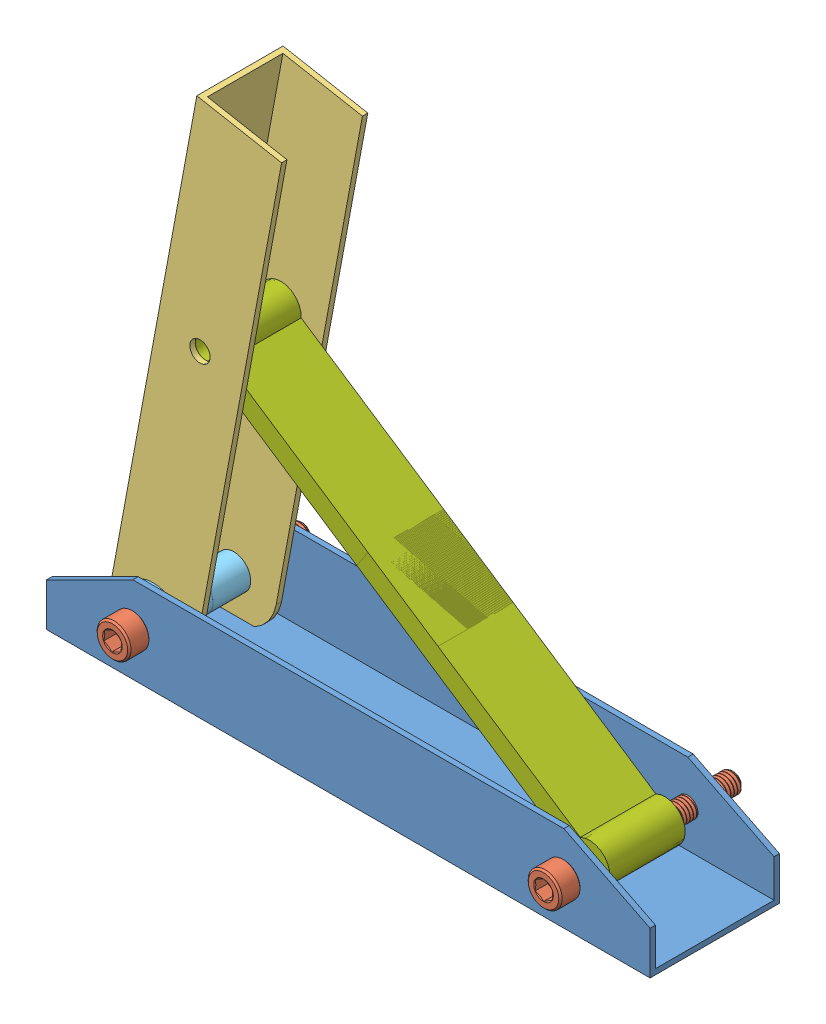
SolidWorks assembly Pedalassem, configuration Default. Lengths in mm.
Overall size (177.8 154.48 56.68).
11 component instances, 7 part files, 21 mates.
Components (placement in the parent):
- PedalBase-1: PedalBase [Default] at (-10.3065 89.3967 179.2393) size (177.8 25.4 38.1)
- 91292A144_18-8 Stainless Steel Socket Head Screw-3: 91292A144_18-8 Stainless Steel Socket Head Screw [91292A144] at (142.0935 102.0967 157.2393) size (10 10 56.68)
- PedalShaft-2: PedalShaft [Default] at (50.2477 82.6782 173.3018) x (0.181898 0.983317 0) z (0 0 1) size (152.4 25.4 25.4)
- 91292A144_18-8 Stainless Steel Socket Head Screw-4: 91292A144_18-8 Stainless Steel Socket Head Screw [91292A144] at (15.0935 102.0967 157.2393) x (0.996533 -0.083195 0) z (0 0 1) size (10 10 56.68)
- 92871A198_18-8 Stainless Steel Unthreaded Spacer-2: 92871A198_18-8 Stainless Steel Unthreaded Spacer [92871A198] at (15.0935 102.0967 176.0643) size (13 13 3.17)
- 92871A198_18-8 Stainless Steel Unthreaded Spacer-3: 92871A198_18-8 Stainless Steel Unthreaded Spacer [92871A198] at (15.0935 102.0967 144.3143) x (0.997287 0.073618 0) z (0 0 1) size (13 13 3.17)
- Nylonbearing-1: Nylonbearing [Default] at (15.0935 102.0967 160.6018) x (0 0 -1) z (1 0 0) size (14.7 18 18)
- Nylonbearing-2: Nylonbearing [Default] at (15.0935 102.0967 160.6018) x (0 0 1) z (-0.923728 -0.383049 0) size (14.7 18 18)
- 90576A115_Medium-Strength Steel Nylon-Insert Locknut-1: 90576A115_Medium-Strength Steel Nylon-Insert Locknut [90576A115] at (15.0935 102.0967 138.1393) x (-0.897632 -0.440747 0) z (0 0 -1) size (10 11.55 6.37)
- demo-1: demo [Default] at (73.5712 143.8787 149.4893) x (0.833738 -0.55216 0) z (0 0 1) size (86.2 12 22.23)
- demo-2: demo [Default] at (97.4764 135.2435 149.4893) x (-0.833738 0.55216 0) z (0 0 1) size (86.2 12 22.23)
Mates (geometry in assembly coordinates):
- Concentric4: concentric anti-aligned: cylinder of PedalBase-1 through (142.0935 102.0967 -49.3607) axis (0 0 1) radius 3; cylinder of 91292A144_18-8 Stainless Steel Socket Head Screw-3 through (142.0935 102.0967 129.2393) axis (0 0 -1) radius 3
- Coincident2: coincident anti-aligned: plane of PedalBase-1 through (218.2935 89.3967 179.2393) normal (0 0 1); plane of 91292A144_18-8 Stainless Steel Socket Head Screw-3 through (137.3435 102.0967 179.2393) normal (0 0 -1)
- Concentric8: concentric anti-aligned: cylinder of PedalBase-1 through (15.0935 102.0967 -49.3607) axis (0 0 1) radius 3; cylinder of 91292A144_18-8 Stainless Steel Socket Head Screw-4 through (15.0935 102.0967 129.2393) axis (0 0 -1) radius 5
- Coincident5: coincident anti-aligned: plane of PedalBase-1 through (218.2935 89.3967 179.2393) normal (0 0 1); plane of 91292A144_18-8 Stainless Steel Socket Head Screw-4 through (10.3599 102.4918 179.2393) normal (0 0 -1)
- Concentric10: concentric aligned: cylinder of 91292A144_18-8 Stainless Steel Socket Head Screw-4 through (15.0935 102.0967 129.2393) axis (0 0 -1) radius 5; cylinder of 92871A198_18-8 Stainless Steel Unthreaded Spacer-2 through (15.0935 102.0967 177.6518) axis (0 0 -1) radius 6.5
- Coincident6: coincident anti-aligned: plane of PedalBase-1 through (218.2935 90.9842 177.6518) normal (0 0 -1); plane of 92871A198_18-8 Stainless Steel Unthreaded Spacer-2 through (15.0935 102.0967 177.6518) normal (0 0 1)
- Concentric11: concentric anti-aligned: cylinder of PedalShaft-2 through (15.0935 102.0967 20.9018) axis (0 0 1) radius 5; cylinder of 91292A144_18-8 Stainless Steel Socket Head Screw-4 through (15.0935 102.0967 129.2393) axis (0 0 -1) radius 5
- Concentric12: concentric aligned: cylinder of 91292A144_18-8 Stainless Steel Socket Head Screw-4 through (15.0935 102.0967 129.2393) axis (0 0 -1) radius 5; cylinder of 92871A198_18-8 Stainless Steel Unthreaded Spacer-3 through (15.0935 102.0967 145.9018) axis (0 0 -1) radius 6.5
- Coincident8: coincident anti-aligned: plane of PedalBase-1 through (218.2935 90.9842 142.7268) normal (0 0 1); plane of 92871A198_18-8 Stainless Steel Unthreaded Spacer-3 through (15.0935 102.0967 142.7268) normal (0 0 -1)
- Concentric13: concentric anti-aligned: cylinder of 91292A144_18-8 Stainless Steel Socket Head Screw-4 through (15.0935 102.0967 129.2393) axis (0 0 -1) radius 5; cylinder of Nylonbearing-1 through (15.0935 102.0967 160.6018) axis (0 0 1) radius 3
- Coincident9: coincident anti-aligned: plane of PedalShaft-2 through (77.969 232.5358 147.9018) normal (0 0 -1); plane of Nylonbearing-1 through (15.0935 111.0967 147.9018) normal (0 0 1)
- Concentric14: concentric aligned: cylinder of 91292A144_18-8 Stainless Steel Socket Head Screw-4 through (15.0935 102.0967 129.2393) axis (0 0 -1) radius 5; cylinder of Nylonbearing-2 through (15.0935 102.0967 160.6018) axis (0 0 -1) radius 3
- Coincident11: coincident anti-aligned: plane of PedalShaft-2 through (77.969 232.5358 173.3018) normal (0 0 1); plane of Nylonbearing-2 through (11.646 110.4102 173.3018) normal (0 0 -1)
- Coincident12: coincident anti-aligned: plane of 92871A198_18-8 Stainless Steel Unthreaded Spacer-3 through (15.0935 102.0967 145.9018) normal (0 0 1); plane of Nylonbearing-1 through (15.0935 105.0967 145.9018) normal (0 0 -1)
- Concentric18: concentric anti-aligned: cylinder of 91292A144_18-8 Stainless Steel Socket Head Screw-4 through (15.0935 102.0967 129.2393) axis (0 0 -1) radius 5; cylinder of 90576A115_Medium-Strength Steel Nylon-Insert Locknut-1 through (15.0935 102.0967 141.1393) axis (0 0 1) radius 2.3505
- Coincident13: coincident anti-aligned: plane of PedalBase-1 through (218.2935 89.3967 141.1393) normal (0 0 -1); plane of 90576A115_Medium-Strength Steel Nylon-Insert Locknut-1 through (15.0935 102.0967 141.1393) normal (0 0 1)
- Concentric20: concentric aligned: cylinder of 91292A144_18-8 Stainless Steel Socket Head Screw-3 through (142.0935 102.0967 129.2393) axis (0 0 -1) radius 5; cylinder of demo-1 through (142.0935 102.0967 171.7143) axis (0 0 -1) radius 6
- Coincident15: coincident anti-aligned: plane of PedalShaft-2 through (76.408 232.8246 149.4893) normal (0 0 1); plane of demo-2 through (28.9541 177.0255 149.4893) normal (0 0 -1)
- Coincident16: coincident anti-aligned: plane of PedalShaft-2 through (76.408 232.8246 149.4893) normal (0 0 1); plane of demo-1 through (142.0935 102.0967 149.4893) normal (0 0 -1)
- Coincident17: coincident aligned: plane of demo-1 through (76.8841 148.8811 171.7143) normal (0.55216 0.833738 0); plane of demo-2 through (97.4764 135.2435 171.7143) normal (0.55216 0.833738 0)
- Coincident18: coincident anti-aligned: circle of PedalShaft-2; cylinder of demo-2 through (28.9541 177.0255 171.7143) axis (0 0 -1) radius 3
